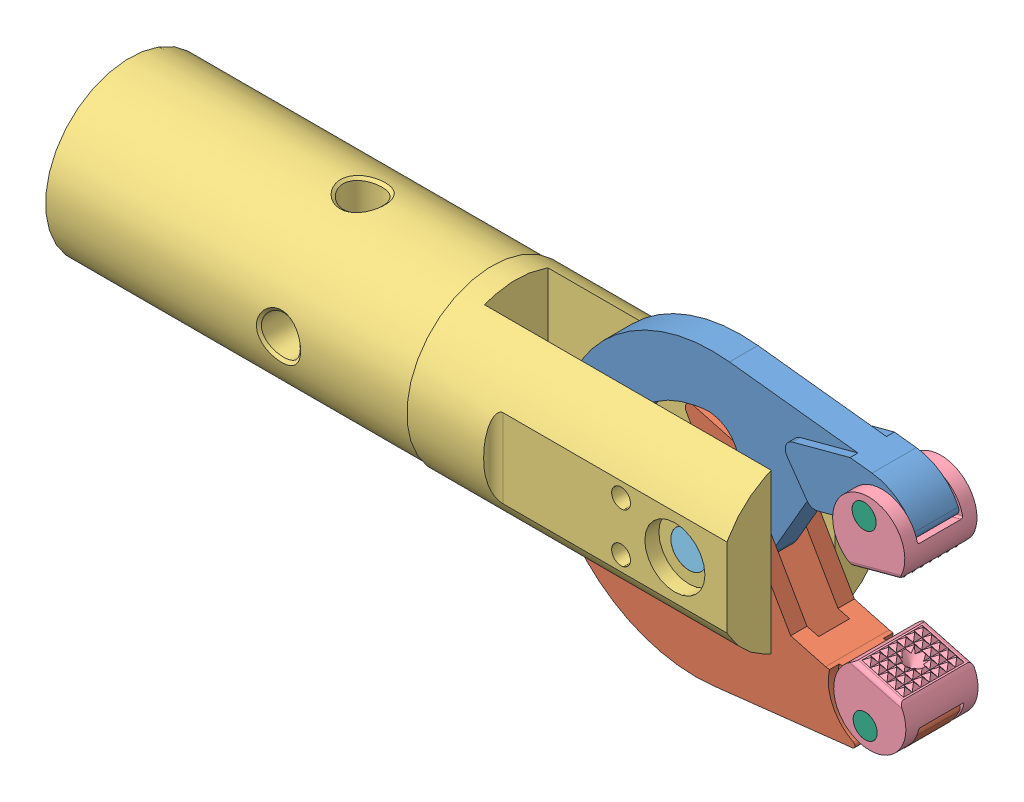
SolidWorks assembly gripper, configuration Default. Lengths in mm.
Overall size (217.78 101.02 45.21).
8 component instances, 6 part files, 19 mates.
Components (placement in the parent):
- Arm1-1: Arm1 [Default] at (-13.7795 0 0.3302) x (-0.965926 -0.258819 0) z (0 0 -1) size (103 45.53 11.68)
- Arm2-1: Arm2 [Default] at (-13.7795 0 0) x (-0.965926 0.258819 0) z (0 0 1) size (103 45.53 16.81)
- Body-1: Body [Default] at origin size (177.75 45.21 45.21)
- Grip-1: Grip [Default] at (27.0062 -19.5273 -0.127) x (0 0 1) z (0.965926 -0.258819 0) size (19.05 17.93 19.05)
- Large_Pin-1: Large_Pin [Default] at (-13.7795 0 -0.1524) size (9.53 9.53 32.77)
- Small_Pin-1: Small_Pin [Default] at (25.79 -24.0662 -0.381) x (-1 0 0) z (0 0 -1) size (6.35 6.35 19.16)
- Small_Pin-2: Small_Pin [Default] at (25.79 24.0662 0.2984) size (6.35 6.35 19.16)
- Grip-2: Grip [Default] at (27.0062 19.5273 0.1524) x (0 0 -1) z (0.965926 0.258819 0) size (19.05 17.93 19.05)
Mates (geometry in assembly coordinates):
- Coincident1: coordinate: point of Body-1; point of assembly
- Concentric1: concentric anti-aligned: cylinder of Body-1 through (-13.7795 0 -22.606) axis (0 0 1) radius 4.7892; cylinder of Large_Pin-1 through (-13.7795 0 18.6436) axis (0 0 -1) radius 4.7625
- Coincident3: coincident aligned: plane of Body-1 through (-13.7795 0 16.3576) normal (0 0 1); plane of Large_Pin-1 through (-13.7795 0 16.3576) normal (0 0 1)
- Concentric2: concentric anti-aligned: cylinder of Arm2-1 through (-13.7795 0 -8.4074) axis (0 0 1) radius 4.7688; cylinder of Large_Pin-1 through (-13.7795 0 18.6436) axis (0 0 -1) radius 4.7625
- Coincident4: coincident anti-aligned: plane of Arm2-1 through (31.6581 -56.8782 8.4074) normal (0 0 1); plane of Body-1 through (-75.692 -22.606 8.4074) normal (0 0 -1)
- Concentric3: concentric anti-aligned: cylinder of Grip-1 through (25.79 -24.0662 -9.652) axis (0 0 1) radius 3.1877; cylinder of Small_Pin-1 through (25.79 -24.0662 12.084) axis (0 0 -1) radius 3.175
- Coincident5: coincident aligned: plane of Grip-1 through (27.0062 -19.5273 9.398) normal (0 0 1); plane of Small_Pin-1 through (25.79 -24.0662 9.398) normal (0 0 1)
- Concentric4: concentric anti-aligned: cylinder of Arm2-1 through (25.79 -24.0662 -8.4074) axis (0 0 1) radius 3.1813; cylinder of Small_Pin-1 through (25.79 -24.0662 12.084) axis (0 0 -1) radius 3.175
- Coincident6: coincident anti-aligned: plane of Arm2-1 through (15.6572 -11.8319 5.842) normal (0 0 1); plane of Grip-1 through (67.0754 -29.3434 5.842) normal (0 0 -1)
- Concentric5: concentric aligned: cylinder of Arm1-1 through (-13.7795 0 6.1722) axis (0 0 -1) radius 4.7688; cylinder of Large_Pin-1 through (-13.7795 0 18.6436) axis (0 0 -1) radius 4.7625
- Coincident7: coincident anti-aligned: plane of Arm1-1 through (31.6581 56.8782 4.0894) normal (0 0 1); plane of Arm2-1 through (31.6581 -56.8782 4.0894) normal (0 0 -1)
- Concentric6: concentric anti-aligned: cylinder of Arm1-1 through (25.79 24.0662 6.1722) axis (0 0 -1) radius 3.1813; cylinder of Small_Pin-2 through (25.79 24.0662 -12.1666) axis (0 0 1) radius 3.175
- Concentric7: concentric anti-aligned: cylinder of Small_Pin-2 through (25.79 24.0662 -12.1666) axis (0 0 1) radius 3.175; cylinder of Grip-2 through (25.79 24.0662 9.6774) axis (0 0 -1) radius 3.1877
- Coincident8: coincident aligned: plane of Small_Pin-2 through (25.79 24.0662 9.6774) normal (0 0 1); plane of Grip-2 through (27.0062 19.5273 9.6774) normal (0 0 1)
- Coincident9: coincident anti-aligned: plane of Arm1-1 through (15.6572 11.8319 6.1722) normal (0 0 1); plane of Grip-2 through (64.38 39.4026 6.1722) normal (0 0 -1)
- Parallel1: parallel anti-aligned: plane of Arm2-1 through (17.3455 -16.6232 -8.4074) normal (0.258819 0.965926 0); plane of Grip-1 through (67.0754 -29.3434 -6.1468) normal (-0.258819 -0.965926 0)
- Parallel2: parallel anti-aligned: plane of Arm1-1 through (17.3455 16.6232 4.0894) normal (0.258819 -0.965926 0); plane of Grip-2 through (67.0754 29.3434 6.1722) normal (-0.258819 0.965926 0)
- Angle6: planar angle = 0.261799 rad aligned: plane of Grip-1 through (67.9619 -22.9807 -8.128) normal (0.258819 0.965926 0); plane of assembly through (0 0 0) normal (0 1 0)
- Angle7: planar angle = 0.261799 rad anti-aligned: plane of Grip-2 through (67.9619 22.9807 8.1534) normal (0.258819 -0.965926 0); plane of assembly through (0 0 0) normal (0 1 0)
